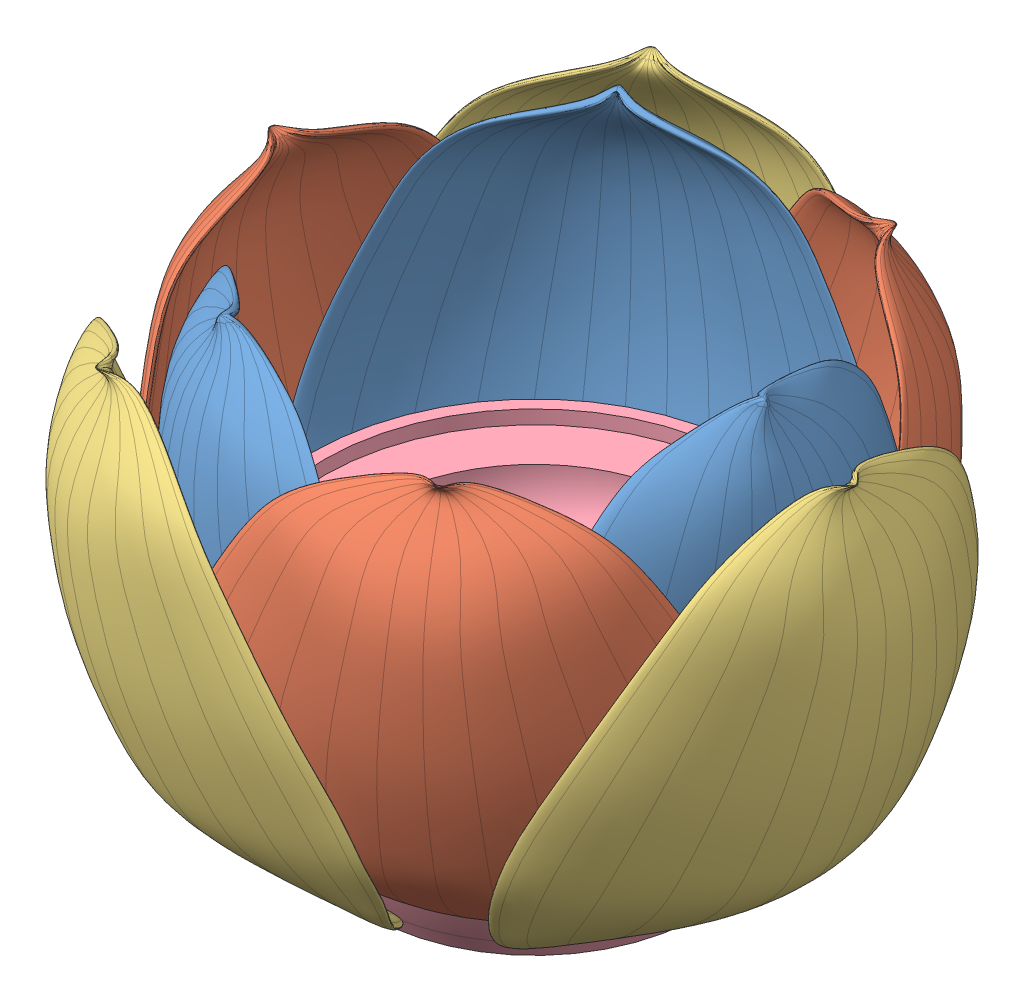
SolidWorks assembly Jasmin v4, configuration Default. Lengths in mm.
Overall size (86.56 65.5 81.5).
4 component instances, 4 part files, 0 mates.
Components (placement in the parent):
- Part a v4-1: Part a v4 [Default] at origin size (66.38 59.24 65.04)
- Part b v1 (1)-1: Part b v1 (1) [Default] x (-1 0 0) z (0 0 -1) size (72.6 56.94 72.4)
- Part c v1-1: Part c v1 [Default] at (-2.0795 0.8219 0) x (-0.996195 -0.087156 0) z (0 0 -1) size (81.77 58.59 81.5)
- Base C v3-1: Base C v3 [Default] at (0 24 0) size (55 25.7 55)
